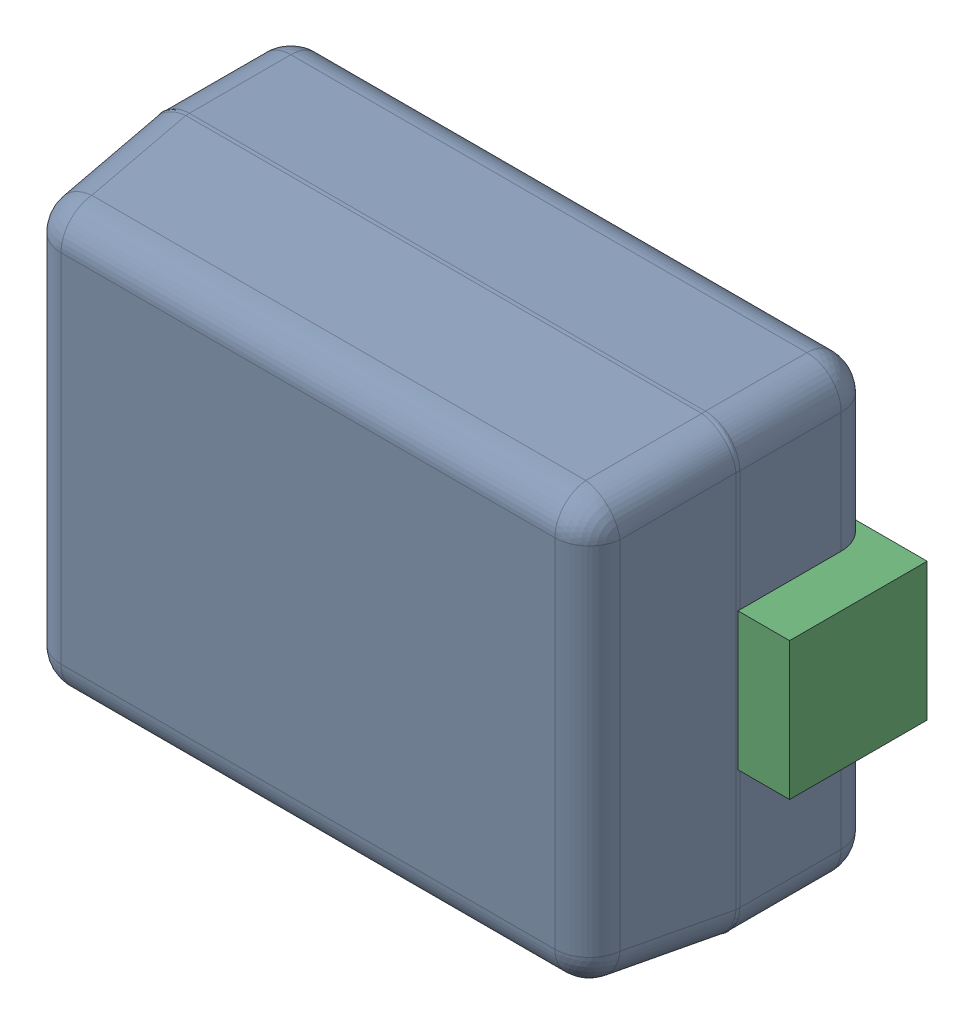
SolidWorks assembly 6297722768.step, configuration Default. Lengths in mm.
Overall size (1 0.66 0.4).
4 component instances, 2 part files, 0 mates.
Components (placement in the parent):
- Body (8).step-1: Body (8).step [Default] at (-0.425 -0.325 0) size (0.85 0.66 0.4)
  - Open CASCADE STEP translator 6.8 15.1.1.step-1: Open CASCADE STEP translator 6.8 15.1.1.step [Default] at origin size (0.85 0.66 0.4)
- lead.step-1: lead.step [Default] at (-0.5 -0.1 0) size (0.19 0.2 0.2)
- lead.step-2: lead.step [Default] at (0.5 0.1 0) x (-1 0 0) z (0 0 1) size (0.19 0.2 0.2)
